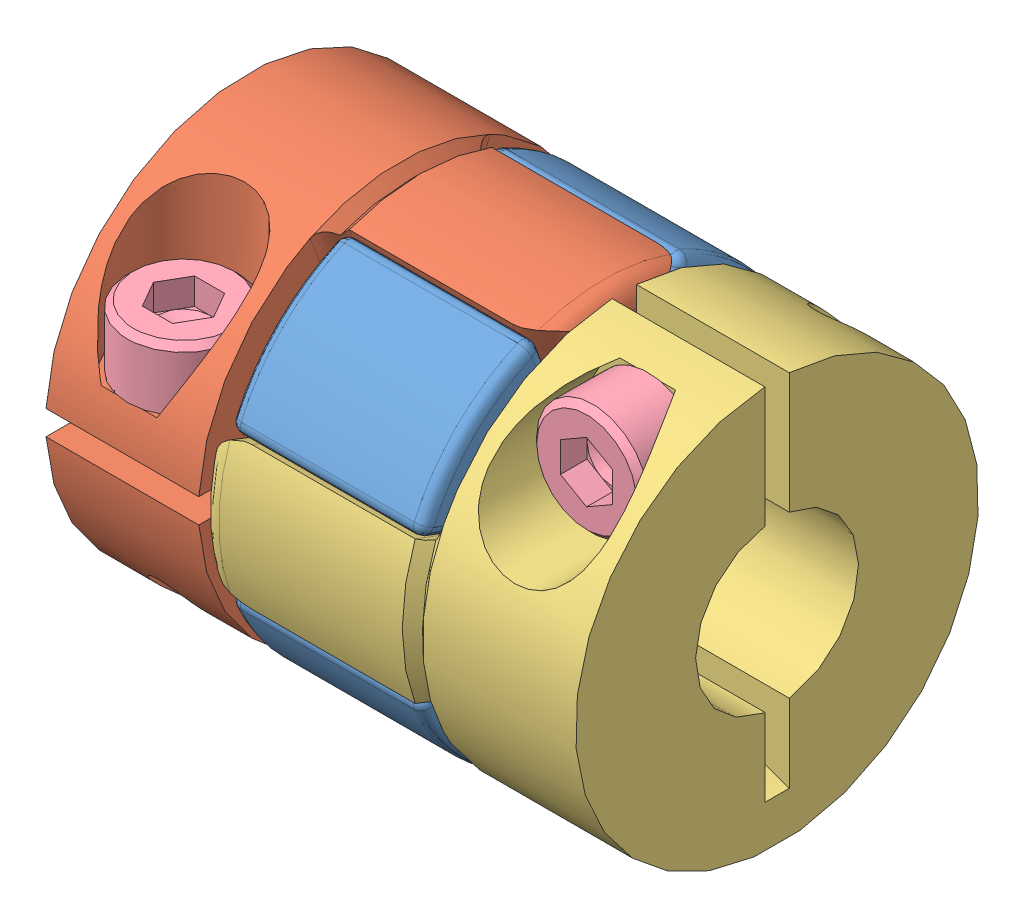
SolidWorks assembly BF-2025-6.35-8, configuration Default. Lengths in mm.
Overall size (26 19.8 19.8).
5 component instances, 4 part files, 10 mates.
Components (placement in the parent):
- Elastomer-1: Elastomer [Default] at origin size (10.5 18.21 18.21)
- 6.35 mm side-1: 6.35 mm side [Default] at (-13 0 0) size (18.66 19.8 19.78)
- 8 mm side-1: 8 mm side [Default] at (13 0 0) x (-1 0 0) z (0 1 0) size (18.66 19.8 19.78)
- socket head cap screw_am-1: socket head cap screw_am [B18.3.1M - 3 x 0.5 x 8 Hex SHCS -- 8NHX] at (-9.25 5.6 6.8818) x (0 -1 0) z (0 0 1) size (11 5.5 5.5)
- socket head cap screw_am-2: socket head cap screw_am [B18.3.1M - 3 x 0.5 x 8 Hex SHCS -- 8NHX] at (9.25 6.8818 5.6) x (0 0 -1) z (1 0 0) size (11 5.5 5.5)
Mates (geometry in assembly coordinates):
- Концентричный1: concentric anti-aligned: cylinder of Elastomer-1 through (-4.7782 0 0) axis (1 0 0) radius 2.6; cylinder of 6.35 mm side-1 through (5.5 0 0) axis (-1 0 0) radius 3.175
- Совпадение1: coincident anti-aligned: plane of Elastomer-1 through (4.75 5.0513 1.9091) normal (0 0.353535 -0.935421); plane of 6.35 mm side-1 through (-5.5 2.97 1.1225) normal (0 -0.353535 0.935421)
- Концентричный2: concentric aligned: cylinder of Elastomer-1 through (-4.7782 0 0) axis (1 0 0) radius 2.6; cylinder of 8 mm side-1 through (-5.5 0 0) axis (1 0 0) radius 4
- Совпадение3: coincident anti-aligned: plane of Elastomer-1 through (4.75 -1.9091 5.0513) normal (0 0.935421 0.353535); plane of 8 mm side-1 through (5.5 -1.1225 2.97) normal (0 -0.935421 -0.353535)
- Совпадение5: coincident anti-aligned: plane of 6.35 mm side-1 through (5.5 0 0) normal (1 0 0); plane of 8 mm side-1 through (5.5 0 0) normal (-1 0 0)
- Расстояние1: distance = 0.25 mm anti-aligned: plane of Elastomer-1 through (5.25 5.3033 5.3033) normal (1 0 0); plane of 8 mm side-1 through (5.5 0 0) normal (-1 0 0)
- Концентричный3: concentric anti-aligned: cone of 6.35 mm side-1 through (-9.25 2.6 6.8818) axis (0 -1 0); cylinder of socket head cap screw_am-1 through (-9.25 37.35 6.8818) axis (0 1 0) radius 2.75
- Совпадение8: coincident anti-aligned: plane of 6.35 mm side-1 through (-9.25 2.6 6.8818) normal (0 1 0); plane of socket head cap screw_am-1 through (-6.5 2.6 6.8818) normal (0 -1 0)
- Концентричный4: concentric anti-aligned: cone of 8 mm side-1 through (9.25 6.8818 2.6) axis (0 0 -1); cylinder of socket head cap screw_am-2 through (9.25 6.8818 37.35) axis (0 0 1) radius 2.75
- Совпадение9: coincident anti-aligned: plane of 8 mm side-1 through (9.25 6.8818 2.6) normal (0 0 1); plane of socket head cap screw_am-2 through (9.25 9.6318 2.6) normal (0 0 -1)
